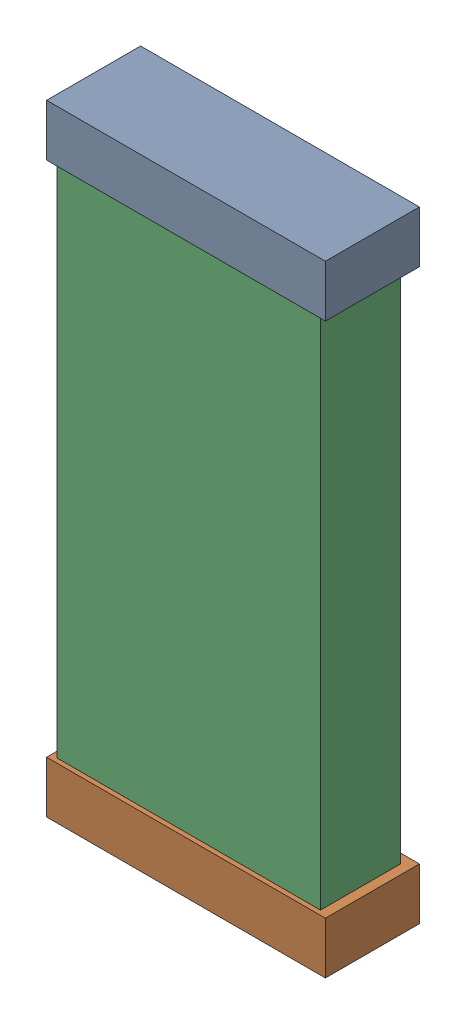
SolidWorks assembly C4, configuration Default. Lengths in mm.
Overall size (1.48 3.3 0.5).
6 component instances, 2 part files, 0 mates.
Components (placement in the parent):
- 744579568_2-1: 744579568_2 [Default] at (26.9059 15.6714 -0.9115) size (1.48 0.28 0.5)
  - Extruded (21)-1: Extruded (21) [Default] at origin size (1.48 0.28 0.5)
- 744579568_3-1: 744579568_3 [Default] at (26.9059 12.6511 -0.9115) size (1.48 0.28 0.5)
  - Extruded (21)-1: Extruded (21) [Default] at origin size (1.48 0.28 0.5)
- 744579440_1-1: 744579440_1 [Default] at (26.8958 14.1462 -0.8615) size (1.4 3.27 0.42)
  - Extruded (22)-1: Extruded (22) [Default] at origin size (1.4 3.27 0.42)
